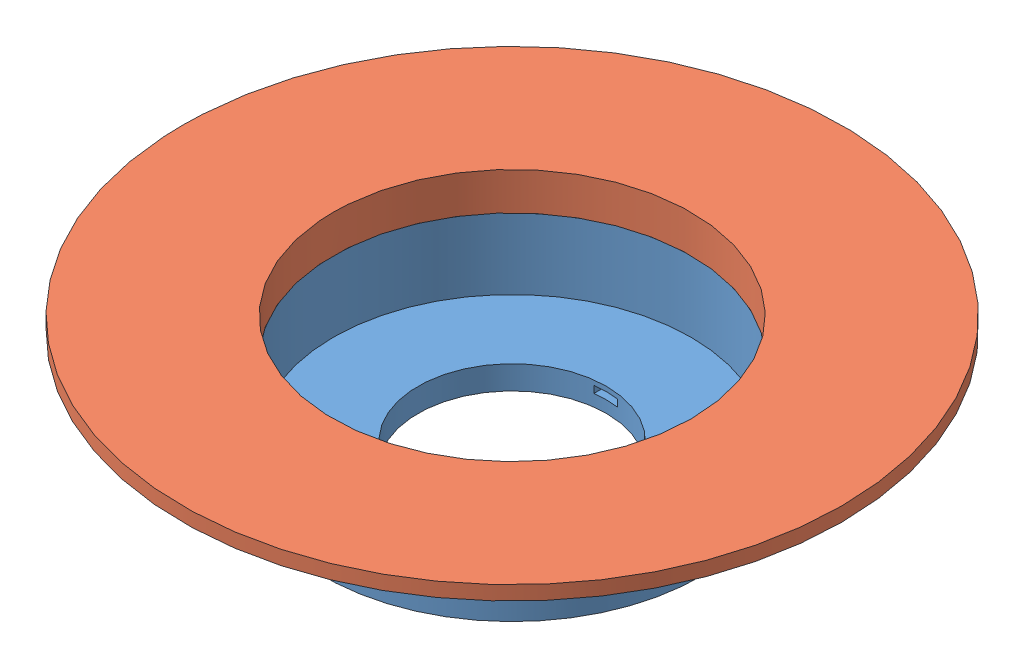
SolidWorks assembly complete, configuration Default. Lengths in mm.
Overall size (140 28 140).
3 component instances, 3 part files, 2 mates.
Components (placement in the parent):
- Part1-2: Part1 [Default] at (74.009 36.7298 45.008) size (80 20 80)
- Part2-2: Part2 [Default] at (32.26 35.7298 67.2632) x (0 0 -1) z (0 -1 0) size (50 20 1.5)
- plate-2: plate [Default] at (54.8093 56.7298 11.6643) x (1 0 0) z (0 -1 0) size (140 140 8)
Mates (geometry in assembly coordinates):
- ProfileCenter2: profile center = 1 mm aligned: plane of Part1-2 through (36.203 36.7298 58.0734) normal (0 1 0); plane of Part2-2 through (36.203 35.7298 58.0734) normal (0 1 0)
- ProfileCenter3: profile center = 0 mm anti-aligned: plane of plate-2 through (36.203 51.7298 58.0734) normal (0 -1 0); plane of Part1-2 through (36.203 51.7298 58.0734) normal (0 1 0)
